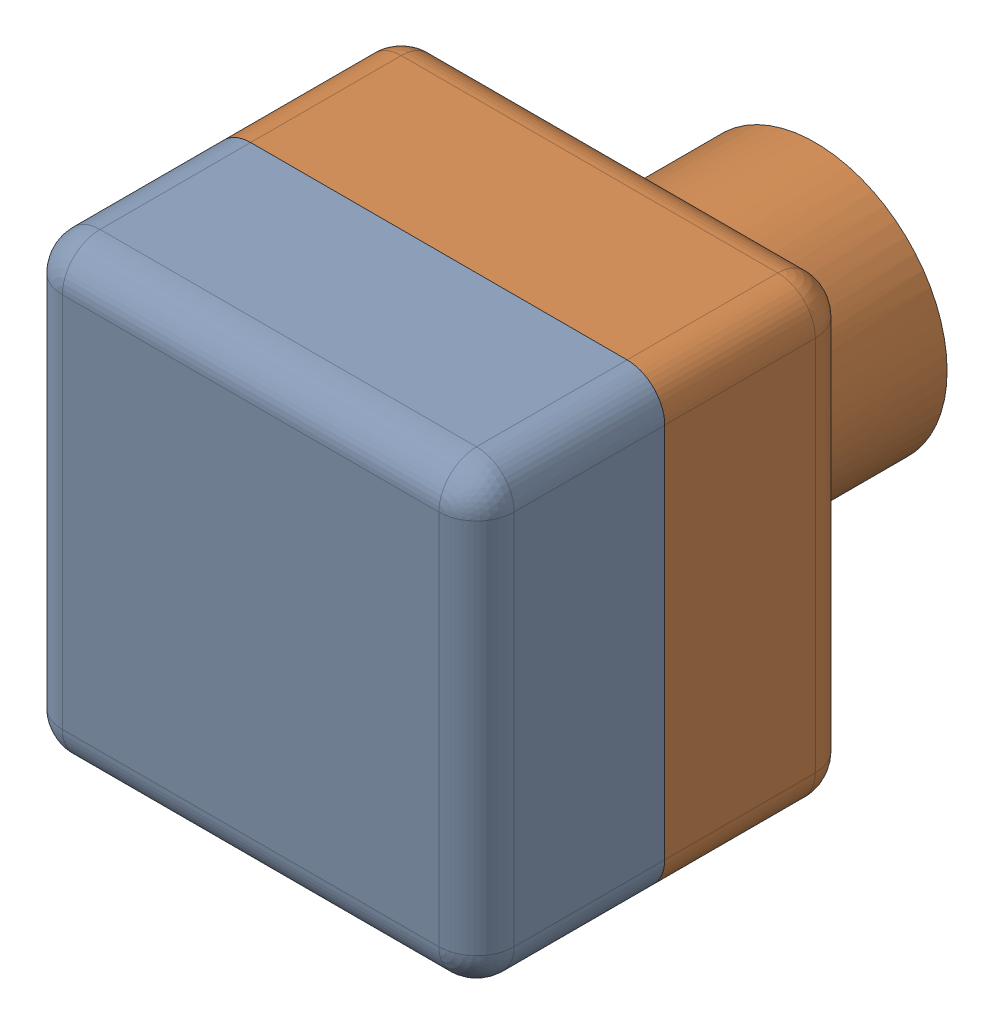
SolidWorks assembly Assem3, configuration Default. Lengths in mm.
Overall size (120 120 150).
2 component instances, 2 part files, 1 mates.
Components (placement in the parent):
- tas2part2-1: tas2part2 [Default] at (42.1715 40.3412 62.7637) size (120 120 80)
- task2part1-1: task2part1 [Default] at (42.1715 40.3412 92.7637) x (1 0 0) z (0 0 -1) size (120 120 100)
Mates (geometry in assembly coordinates):
- ProfileCenter1: profile center: plane of tas2part2-1 through (92.1715 90.3412 92.7637) normal (0 0 -1); plane of task2part1-1 through (42.1715 40.3412 92.7637) normal (0 0 1)
